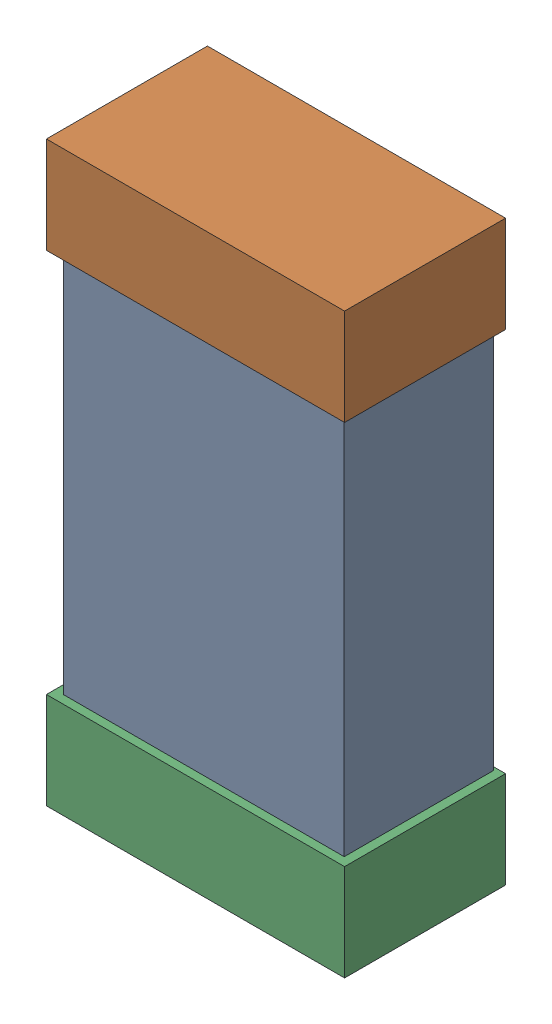
SolidWorks assembly R23, configuration Default. Lengths in mm.
Overall size (0.85 1.65 0.46).
6 component instances, 2 part files, 0 mates.
Components (placement in the parent):
- 432124816_53-1: 432124816_53 [Default] at (33.9499 43.4999 -0.8615) size (0.8 1.5 0.42)
  - Extruded (1)-1: Extruded (1) [Default] at origin size (0.8 1.5 0.42)
- 432138512_106-1: 432138512_106 [Default] at (33.9499 44.1857 -0.8715) size (0.85 0.28 0.46)
  - Extruded-1: Extruded [Default] at origin size (0.85 0.28 0.46)
- 432138512_107-1: 432138512_107 [Default] at (33.9499 42.8142 -0.8715) size (0.85 0.28 0.46)
  - Extruded-1: Extruded [Default] at origin size (0.85 0.28 0.46)
